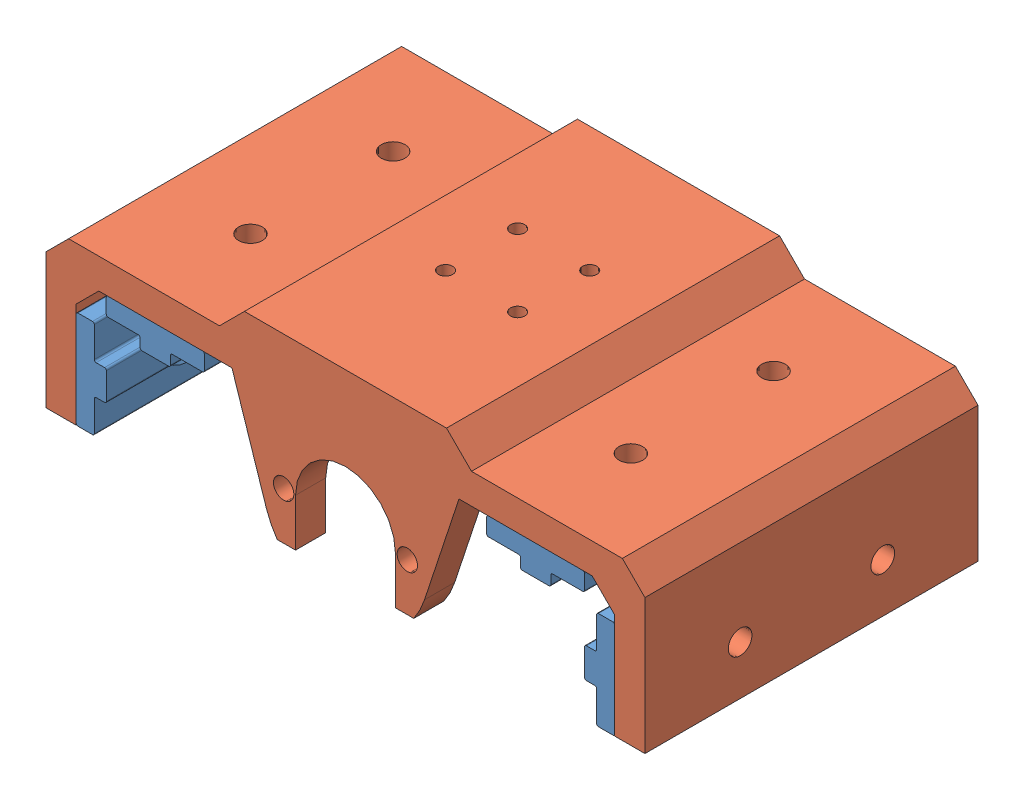
SolidWorks assembly Clamp Carriage Assembly, configuration Default. Lengths in mm.
Overall size (125.95 38.42 70.04).
5 component instances, 2 part files, 12 mates.
Components (placement in the parent):
- Clamp Carriage Bearing-1: Clamp Carriage Bearing [Default] at (-7.624 47.1446 10.2722) size (6.35 20.62 70.04)
- Clamp Carriage Bearing-2: Clamp Carriage Bearing [Default] at (98.006 47.1446 10.2722) x (-1 0 0) z (0 0 1) size (6.35 20.62 70.04)
- Clamp Carriage Bearing-3: Clamp Carriage Bearing [Default] at (5.196 59.8446 10.2722) x (0 -1 0) z (0 0 1) size (6.35 20.62 70.04)
- Clamp Carriage Bearing-4: Clamp Carriage Bearing [Default] at (85.186 59.8446 10.2722) x (0 -1 0) z (0 0 1) size (6.35 20.62 70.04)
- Clamp Carriage Body-1: Clamp Carriage Body [Default] at (45.191 36.8346 -47.0678) size (125.95 38.42 70.04)
Mates (geometry in assembly coordinates):
- Coincident7: coincident: plane of Clamp Carriage Bearing-3 through (15.1274 63.6546 -47.0678) normal (0 1 0); plane of Clamp Carriage Body-1 through (-6.684 63.6546 22.9722) normal (0 -1 0)
- Coincident8: coincident: plane of Clamp Carriage Bearing-4 through (95.1174 63.6546 -47.0678) normal (0 1 0); plane of Clamp Carriage Body-1 through (-6.684 63.6546 22.9722) normal (0 -1 0)
- Coincident9: coincident: plane of Clamp Carriage Bearing-1 through (-11.434 57.076 -47.0678) normal (-1 0 0); plane of Clamp Carriage Body-1 through (-11.434 36.8346 22.9722) normal (1 0 0)
- Coincident10: coincident: plane of Clamp Carriage Bearing-2 through (101.816 37.2132 -47.0678) normal (1 0 0); plane of Clamp Carriage Body-1 through (101.816 36.8346 22.9722) normal (-1 0 0)
- Distance4: distance = 16.63 mm: moEndPointRef_w of Clamp Carriage Bearing-3; plane of Clamp Carriage Body-1 through (-11.434 36.8346 22.9722) normal (1 0 0)
- Distance5: distance = 16.63 mm: moEndPointRef_w of Clamp Carriage Bearing-4; plane of Clamp Carriage Body-1 through (101.816 36.8346 22.9722) normal (-1 0 0)
- Distance6: distance = 16.51 mm: plane of Clamp Carriage Body-1 through (-6.684 63.6546 22.9722) normal (0 -1 0); moEndPointRef_w of Clamp Carriage Bearing-1
- Coincident12: coincident: plane of Clamp Carriage Bearing-1 through (-11.053 36.8322 -47.0678) normal (0 -1 0); plane of Clamp Carriage Bearing-2 through (98.387 36.8322 -47.0678) normal (0 -1 0)
- Coincident13: coincident: plane of Clamp Carriage Bearing-1 through (-11.053 57.076 -47.0678) normal (0 0 -1); plane of Clamp Carriage Body-1 through (45.191 36.8346 -47.0678) normal (0 0 -1)
- Coincident14: coincident: plane of Clamp Carriage Bearing-4 through (95.1174 63.2736 -47.0678) normal (0 0 -1); plane of Clamp Carriage Body-1 through (45.191 36.8346 -47.0678) normal (0 0 -1)
- Coincident15: coincident: plane of Clamp Carriage Bearing-3 through (15.1274 63.2736 -47.0678) normal (0 0 -1); plane of Clamp Carriage Body-1 through (45.191 36.8346 -47.0678) normal (0 0 -1)
- Coincident16: coincident: plane of Clamp Carriage Bearing-2 through (101.435 37.2132 -47.0678) normal (0 0 -1); plane of Clamp Carriage Body-1 through (45.191 36.8346 -47.0678) normal (0 0 -1)
